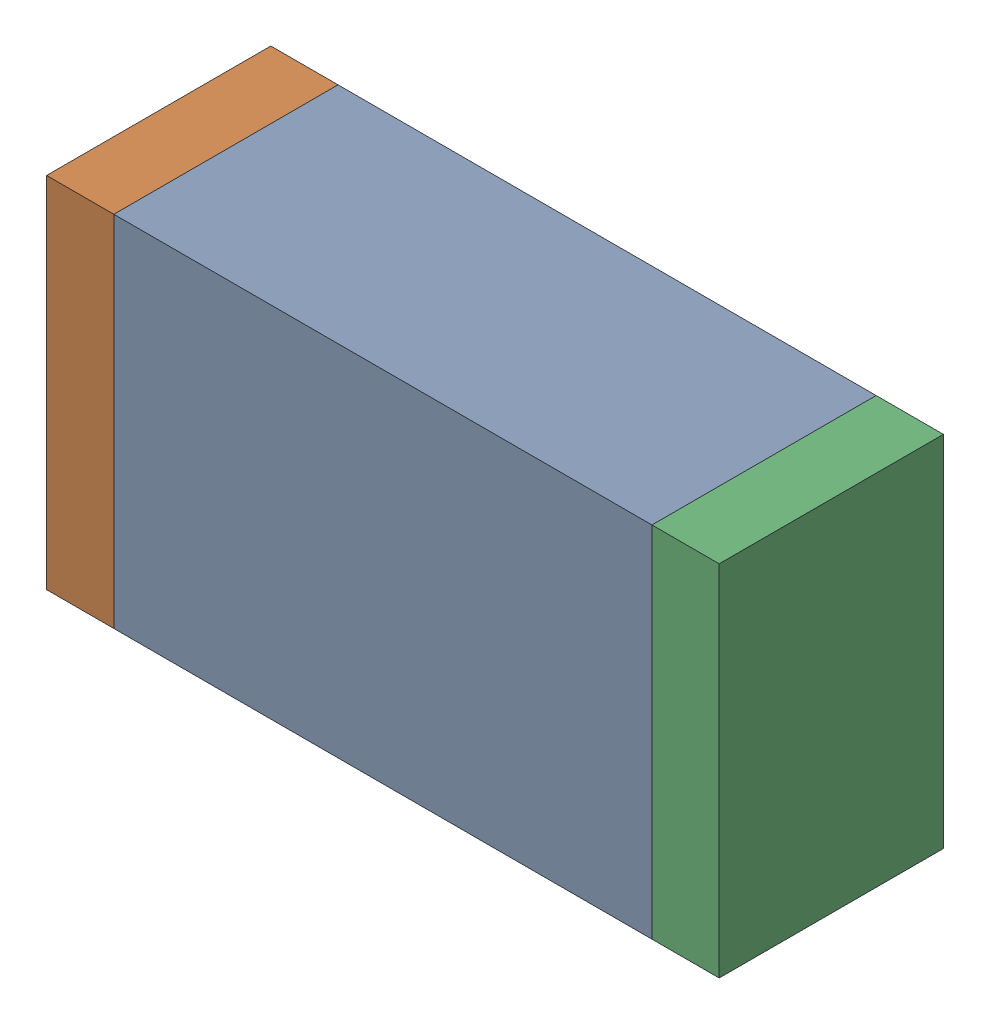
SolidWorks assembly D29, configuration Default. Lengths in mm.
Overall size (1.5 0.8 0.5).
6 component instances, 2 part files, 0 mates.
Components (placement in the parent):
- 836752368-1: 836752368 [Default] at (107.2 74.25 0) size (1.2 0.8 0.5)
  - Extruded-1: Extruded [Default] at origin size (1.2 0.8 0.5)
- 836752496-1: 836752496 [Default] at (106.525 74.25 0) size (0.15 0.8 0.5)
  - Extruded_2-1: Extruded_2 [Default] at origin size (0.15 0.8 0.5)
- 836752496-2: 836752496 [Default] at (107.875 74.25 0) size (0.15 0.8 0.5)
  - Extruded_2-1: Extruded_2 [Default] at origin size (0.15 0.8 0.5)
